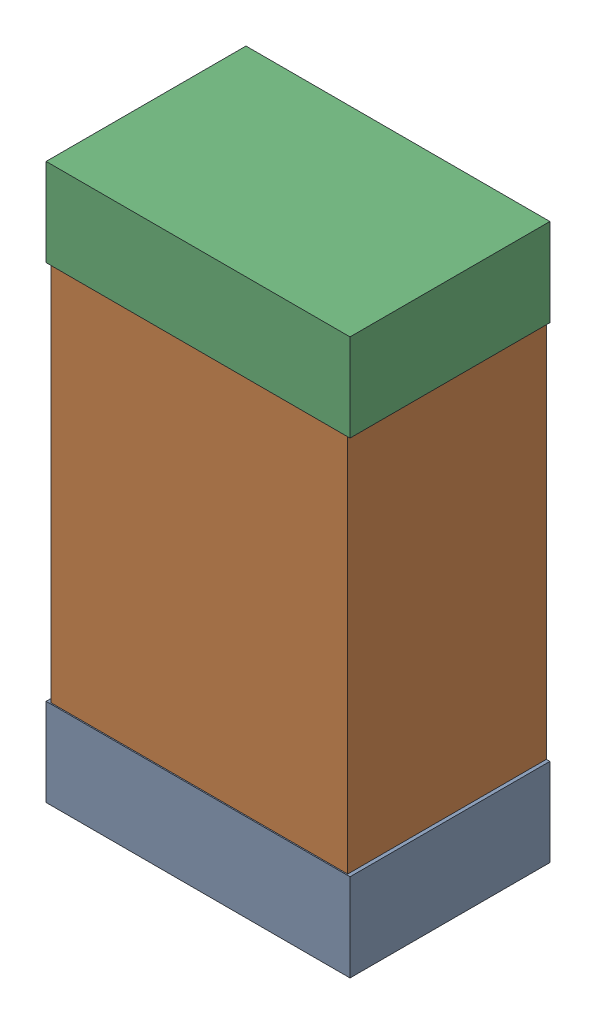
SolidWorks assembly R3000Kanaloa_v2.0.0_GPIO_b, configuration Default. Lengths in mm.
Overall size (1.3 2.38 0.85).
6 component instances, 2 part files, 0 mates.
Components (placement in the parent):
- 330415056-1: 330415056 [Default] at (43.307 35.83 0) size (1.3 0.38 0.85)
  - Extruded_2-1: Extruded_2 [Default] at origin size (1.3 0.38 0.85)
- 352877008-1: 352877008 [Default] at (43.307 36.83 0) size (1.27 2.2 0.85)
  - Extruded_3-1: Extruded_3 [Default] at origin size (1.27 2.2 0.85)
- 330415056-2: 330415056 [Default] at (43.307 37.83 0) size (1.3 0.38 0.85)
  - Extruded_2-1: Extruded_2 [Default] at origin size (1.3 0.38 0.85)
